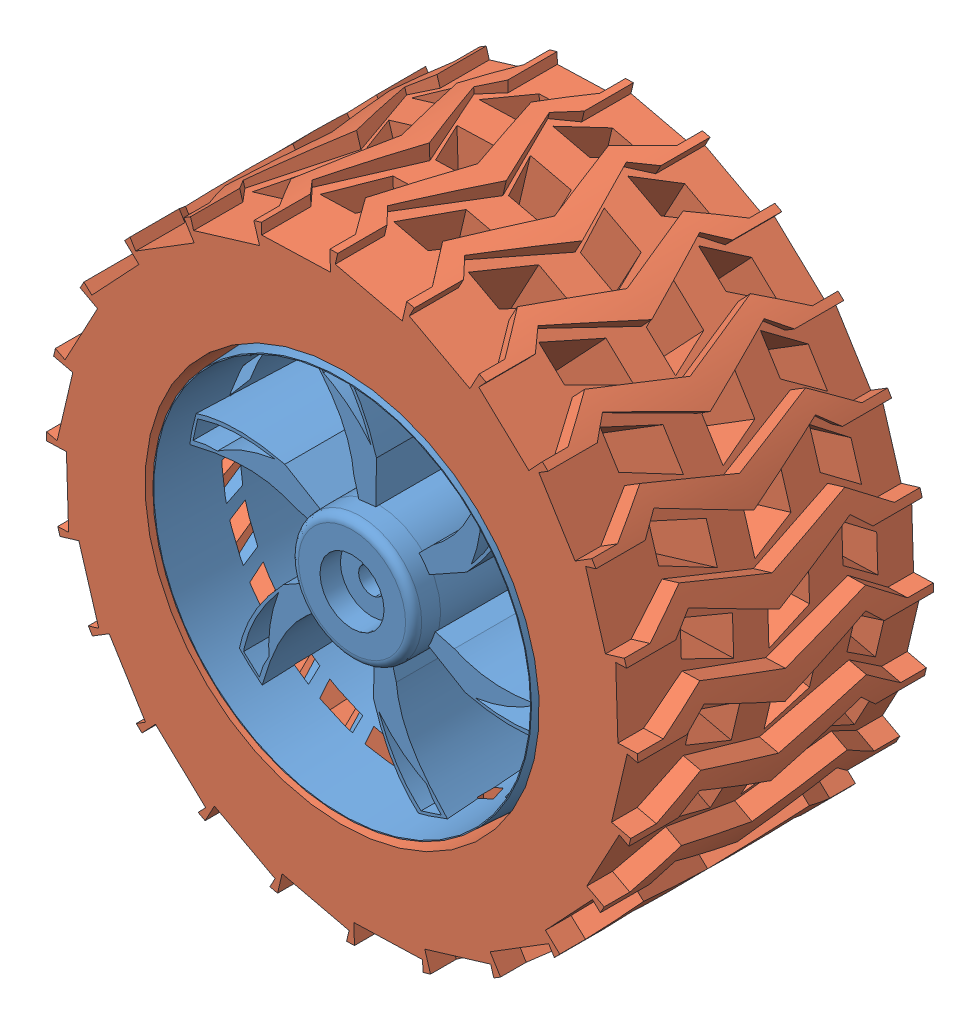
SolidWorks assembly Wheel assembly, configuration Default. Lengths in mm.
Overall size (127.22 127.22 45).
2 component instances, 2 part files, 4 mates.
Components (placement in the parent):
- wheel-1: wheel [Default] at (25.5285 33.2647 43.0752) size (60 60 45)
- tyre-1: tyre [Default] at (25.5285 33.2647 65.5752) x (0 0 -1) z (0.684345 0.729158 0) size (45 90 90)
Mates (geometry in assembly coordinates):
- Coincident1: coincident aligned: circle of wheel-1; cylinder of tyre-1 through (25.5285 33.2647 20.5752) axis (0 0 1) radius 30
- Width1: width anti-aligned: plane of tyre-1 through (25.5285 33.2647 65.5752) normal (0 0 1); plane of wheel-1 through (25.5285 33.2647 20.5752) normal (0 0 -1); plane of tyre-1 through (25.5285 33.2647 20.5752) normal (0 0 -1); plane of wheel-1 through (25.5285 33.2647 65.5752) normal (0 0 1)
- Concentric2: concentric anti-aligned: cone of wheel-1 through (25.5285 33.2647 60.0752) axis (0 0 -1); cylinder of motor12v-2 through (25.5285 33.2647 58.0752) axis (0 0 1) radius 4.725
- Coincident2: coincident anti-aligned: plane of wheel-1 through (25.5285 33.2647 64.0752) normal (0 0 1); plane of motor12v-2 through (25.5285 33.2647 64.0752) normal (0 0 -1)
